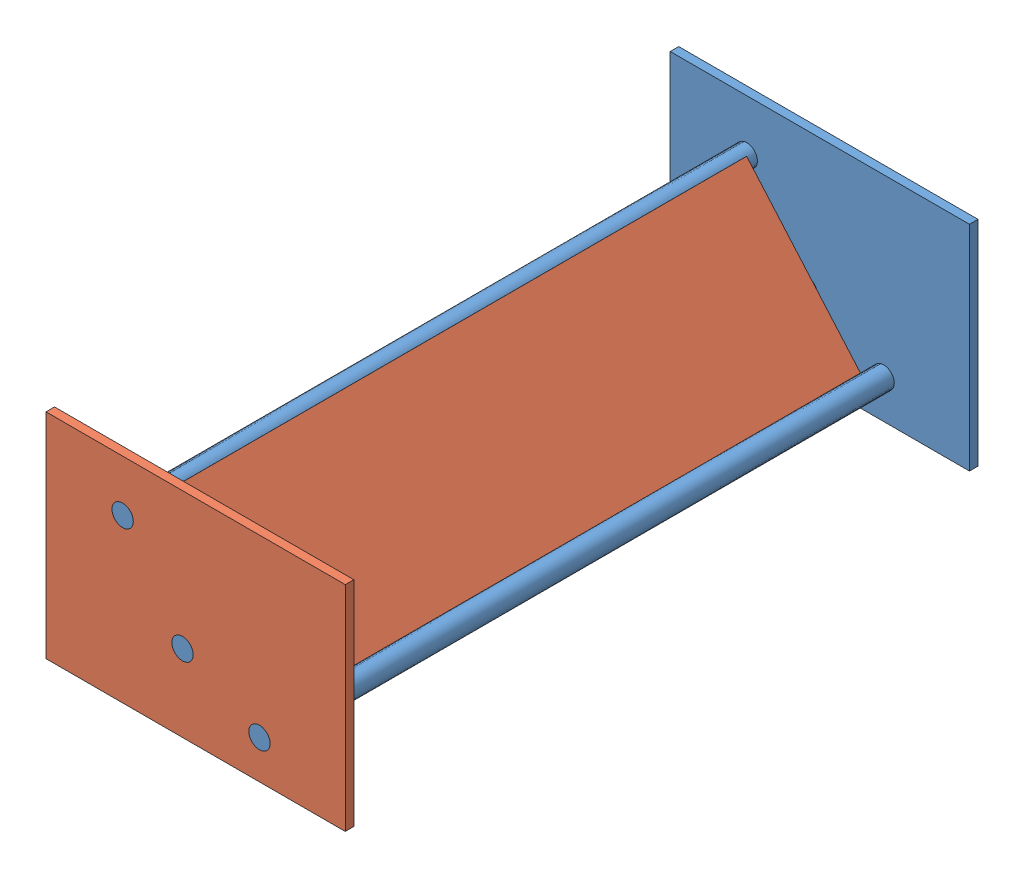
SolidWorks assembly Ensamblaje1, configuration Predeterminado. Lengths in mm.
Overall size (350 327.33 740).
3 component instances, 3 part files, 4 mates.
Components (placement in the parent):
- Rodillos 1zquierdo-1: Rodillos 1zquierdo [Predeterminado] at (-105.9317 12.6585 740) size (350 250 740)
- Rodillos Derecho-1: Rodillos Derecho [Predeterminado] at (-105.9317 12.6585 1470) size (350 250 720)
- Cabezal de impresora-1: Cabezal de impresora [Predeterminado] at (-221.0074 -173.8283 1096.368) x (0.656499 -0.754327 0) z (0 0 1) size (42 200 42)
Mates (geometry in assembly coordinates):
- Coincidente1: coincident aligned: plane of Rodillos 1zquierdo-1 through (-31.3131 -67.3415 1480) normal (0 0 1); plane of Rodillos Derecho-1 through (-105.9317 12.6585 1480) normal (0 0 1)
- Concéntrica1: concentric aligned: cylinder of Rodillos 1zquierdo-1 through (-191.3131 77.6585 1480) axis (0 0 -1) radius 12.5; cylinder of Rodillos Derecho-1 through (-191.3131 77.6585 1480) axis (0 0 -1) radius 12.5
- Coincidente2: coincident anti-aligned: plane of Rodillos Derecho-1 through (-181.884 85.8647 760) normal (-0.754327 -0.656499 0); plane of Cabezal de impresora-1 through (-70.142 -42.5285 1096.368) normal (0.754327 0.656499 0)
- Concéntrica2: concentric aligned: cylinder of Rodillos 1zquierdo-1 through (-31.3131 -67.3415 1480) axis (0 0 -1) radius 12.5; cylinder of Rodillos Derecho-1 through (-31.3131 -67.3415 1480) axis (0 0 -1) radius 12.5
